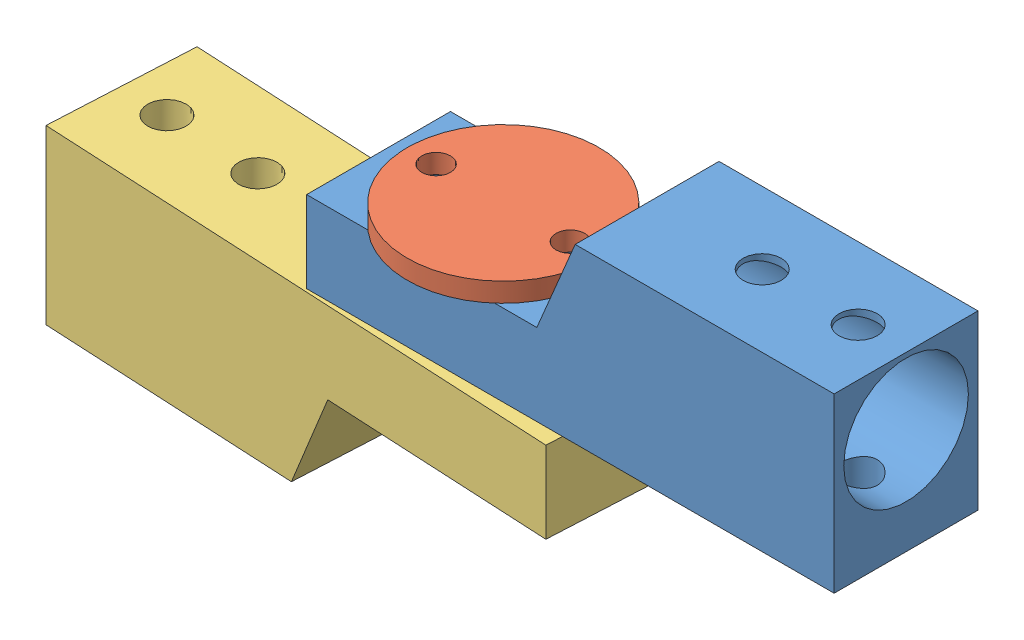
SolidWorks assembly Joint_Assembly, configuration Default. Lengths in mm.
Overall size (84.33 37 20).
3 component instances, 3 part files, 5 mates.
Components (placement in the parent):
- joint_part_2-1: joint_part_2 [Default] at (21.966 12.8341 37.3194) size (55 18 15)
- joint_part_3-1: joint_part_3 [Default] at (4.966 -0.4159 37.3194) x (-1 0 0) z (0 1 0) size (20 20 23.5)
- joint_part_5-1: joint_part_5 [Default] at (-12.0118 -10.1659 36.4506) x (-0.998693 0 -0.051104) z (-0.051104 0 0.998693) size (55 18 15)
Mates (geometry in assembly coordinates):
- Concentric2: concentric aligned: cylinder of joint_part_2-1 through (4.966 1.8341 37.3194) axis (0 1 0) radius 3; cylinder of joint_part_3-1 through (4.966 -11.1659 37.3194) axis (0 1 0) radius 3
- Coincident2: coincident anti-aligned: plane of joint_part_2-1 through (21.966 10.3341 37.3194) normal (0 1 0); plane of joint_part_3-1 through (4.966 10.3341 37.3194) normal (0 -1 0)
- Concentric3: concentric aligned: cylinder of joint_part_2-1 through (-2.034 1.8341 37.3194) axis (0 1 0) radius 1.5; cylinder of joint_part_3-1 through (-2.034 -11.1669 37.3194) axis (0 1 0) radius 1.5
- Distance1: distance = 1 mm anti-aligned: plane of joint_part_5-1 through (-36.9791 0.8341 35.173) normal (0 1 0); plane of joint_part_2-1 through (46.966 1.8341 37.3194) normal (0 -1 0)
- Concentric4: concentric anti-aligned: cylinder of joint_part_3-1 through (4.966 -11.1659 37.3194) axis (0 1 0) radius 3; cylinder of joint_part_5-1 through (4.966 0.8341 37.3194) axis (0 -1 0) radius 3
